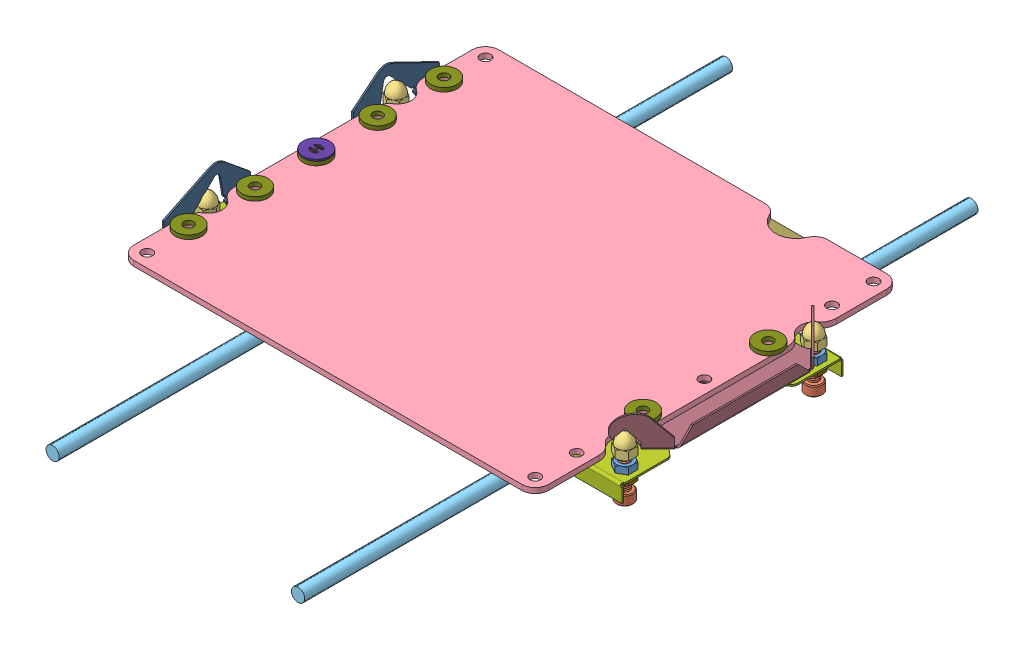
SolidWorks assembly Mendel_BedMount, configuration Default. Lengths in mm.
Overall size (275.81 70.12 406).
45 component instances, 20 part files, 73 mates.
Components (placement in the parent):
- M6_NutPress_99437A160-1: M6_NutPress_99437A160 [99437A160] at (-126 -5.9 57) x (0.191683 0 -0.981457) z (0 1 0) size (10 11.55 5.74)
- M6x24_95263A561-1: M6x24_95263A561 [95263A561] at (-126 4.0374 57) x (-0.390888 0 -0.920438) z (0 1 0) size (10 10 31.64)
- M6_NutAcorn_94000A038-1: M6_NutAcorn_94000A038 [94000A038] at (-126 -2.9626 57) x (-0.871894 0 0.489695) z (0 -1 0) size (10 11.55 12.42)
- GlassBed-1: GlassBed [Default] at origin size (250 3.17 220)
- Yaxis_Rod-1: Yaxis_Rod [Default] at (-74 -30 202) size (8 8 406)
- Yaxis_Rod-2: Yaxis_Rod [Default] at (74 -30 202) size (8 8 406)
- 8x25x37mm_LMUD8-1: 8x25x37mm_LMUD8 [Default] at (74 -30 -44) x (0 0 -1) z (-0.99999 -0.004469 0) size (37 15 15)
- 8x25x37mm_LMUD8-2: 8x25x37mm_LMUD8 [Default] at (74 -30 44) x (0 0 -1) z (0.967363 -0.253393 0) size (37 15 15)
- AluminumFrame^Mendel_BedMount-1: AluminumFrame^Mendel_BedMount [Default] at origin size (268 25 133.45)
- V-reinforcement^Mendel_BedMount-1: V-reinforcement^Mendel_BedMount [Default] at origin size (107 35.99 131.12)
- M6_NutAcorn_94000A038-2: M6_NutAcorn_94000A038 [94000A038] at (-126 -2.9626 -57) x (1 0 0) z (0 -1 0) size (10 11.55 12.42)
- M6_NutAcorn_94000A038-3: M6_NutAcorn_94000A038 [94000A038] at (126 -2.9626 -57) x (1 0 0) z (0 -1 0) size (10 11.55 12.42)
- M6_NutAcorn_94000A038-4: M6_NutAcorn_94000A038 [94000A038] at (126 -2.9626 57) x (1 0 0) z (0 -1 0) size (10 11.55 12.42)
- M6_NutPress_99437A160-2: M6_NutPress_99437A160 [99437A160] at (-126 -5.9 -57) x (1 0 0) z (0 1 0) size (10 11.55 5.74)
- M6_NutPress_99437A160-3: M6_NutPress_99437A160 [99437A160] at (126 -5.9 -57) x (1 0 0) z (0 1 0) size (10 11.55 5.74)
- M6_NutPress_99437A160-4: M6_NutPress_99437A160 [99437A160] at (126 -5.9 57) x (1 0 0) z (0 1 0) size (10 11.55 5.74)
- M6x24_95263A561-2: M6x24_95263A561 [95263A561] at (-126 4.0374 -57) x (0.977589 0 -0.210522) z (0 1 0) size (10 10 31.64)
- M6x24_95263A561-3: M6x24_95263A561 [95263A561] at (126 4.0374 -57) x (0.987041 0 0.160467) z (0 1 0) size (10 10 31.64)
- M6x24_95263A561-4: M6x24_95263A561 [95263A561] at (126 4.0374 57) x (-0.559971 0 -0.828512) z (0 1 0) size (10 10 31.64)
- Nut_M6_91828A251-1: Nut_M6_91828A251 [91828A251] at (-126 -13.516 -57) size (10 5.37 11.55)
- Nut_M6_91828A251-2: Nut_M6_91828A251 [91828A251] at (-126 -13.516 57) size (10 5.37 11.55)
- Nut_M6_91828A251-3: Nut_M6_91828A251 [91828A251] at (126 -13.516 57) size (10 5.37 11.55)
- Nut_M6_91828A251-4: Nut_M6_91828A251 [91828A251] at (126 -13.516 -57) size (10 5.37 11.55)
- Kinematic_A^Mendel_BedMount-1: Kinematic_A^Mendel_BedMount [Default] at origin size (31.19 23.27 52) (virtual)
- Kinematic_B^Mendel_BedMount-1: Kinematic_B^Mendel_BedMount [Default] at origin (suppressed, hidden, virtual)
- Kinematic_B^Mendel_BedMount-4: Kinematic_B^Mendel_BedMount [Default_Mirror] at origin (suppressed, hidden, virtual)
- Kinematic_A^Mendel_BedMount-4: Kinematic_A^Mendel_BedMount [_MirrorDefault] at origin size (31.19 23.27 52) (virtual)
- BearingClamp-1: BearingClamp [Default] at origin size (17.03 28.52 27.15) (hidden)
- BearingClamp-2: BearingClamp [Default] at (0 0 -88) size (17.03 28.52 27.15) (hidden)
- PCBheater-1: PCBheater [Default] at (0 -1.75 0) x (0 0 1) z (-1 0 0) size (214 1.75 214)
- Kinematic_C^Mendel_BedMount-1: Kinematic_C^Mendel_BedMount [Default] at origin size (42.61 21.87 125.3) (virtual)
- bearing_5x16x5-1: bearing_5x16x5 [Default] at (-74 -18 0) size (5 16 16)
- bearing_5x16x5-2: bearing_5x16x5 [Default] at (-74 -42 0) size (5 16 16)
- Bearing_Printed^Mendel_BedMount-1: Bearing_Printed^Mendel_BedMount [Default] at origin size (25 24.88 38) (virtual)
- 1-4_silicone_99604A115-1: 1-4_silicone_99604A115 [99604A115] at (-117 3.175 37) x (1 0 0) z (0 -1 0) size (15.88 15.88 2.36)
- 1-4_silicone_99604A115-2: 1-4_silicone_99604A115 [99604A115] at (-117 3.175 -37) x (1 0 0) z (0 -1 0) size (15.88 15.88 2.36)
- 1-4_silicone_99604A115-3: 1-4_silicone_99604A115 [99604A115] at (-117 3.175 77) x (1 0 0) z (0 -1 0) size (15.88 15.88 2.36)
- 1-4_silicone_99604A115-4: 1-4_silicone_99604A115 [99604A115] at (-117 3.175 -77) x (1 0 0) z (0 -1 0) size (15.88 15.88 2.36)
- 1-4_silicone_99604A115-5: 1-4_silicone_99604A115 [99604A115] at (-117.0025 3.175 0) x (1 0 0) z (0 -1 0) size (15.88 15.88 2.36)
- 1-4_silicone_99604A115-7: 1-4_silicone_99604A115 [99604A115] at (118.5 3.175 -37) x (0.283432 0 -0.958992) z (0 -1 0) size (15.88 15.88 2.36)
- 1-4_silicone_99604A115-8: 1-4_silicone_99604A115 [99604A115] at (117 3.175 37) x (1 0 0) z (0 -1 0) size (15.88 15.88 2.36)
- Spring_clamp^Mendel_BedMount-1: Spring_clamp^Mendel_BedMount [Default] at origin size (15.88 1.02 15.88) (virtual)
- AWS5_15-1: AWS5_15 [Default] at (-116.47 -8.0769 0.334) x (0.015915 0.999378 -0.031454) z (0.999709 -0.015333 0.018643) size (16.2 5 5)
- WSSS10-5-2.5-1: WSSS10-5-2.5 [Default] at (-69 -18 0) x (0 1 0) z (0 0 1) size (10 2.5 10)
- WSSS10-5-2.5-2: WSSS10-5-2.5 [Default] at (-69 -42 0) x (0 1 0) z (0 0 1) size (10 2.5 10)
Mates (geometry in assembly coordinates):
- Coincident5: coincident anti-aligned: cylinder of M6x24_95263A561-1 through (-126 -26.9626 57) axis (0 1 0) radius 5; circle of M6_NutAcorn_94000A038-1
- Concentric2: concentric anti-aligned: circle of M6_NutPress_99437A160-1; cylinder of M6x24_95263A561-1 through (-126 -26.9626 57) axis (0 1 0) radius 5
- Distance1: distance = 18 mm anti-aligned: plane of M6_NutAcorn_94000A038-1 through (-125.8814 -2.9626 47.0007) normal (0 -1 0); plane of M6x24_95263A561-1 through (-126 -20.9626 57) normal (0 1 0)
- Coincident9: coincident aligned: plane of GlassBed-1 through (0 0 0) normal (0 0 1); plane of assembly through (0 0 0) normal (0 0 1)
- Coincident10: coincident aligned: plane of GlassBed-1 through (0 0 0) normal (0 1 0); plane of assembly through (0 0 0) normal (0 1 0)
- Coincident11: coincident aligned: plane of GlassBed-1 through (0 0 0) normal (1 0 0); plane of assembly through (0 0 0) normal (1 0 0)
- Coincident16: coincident: plane of Yaxis_Rod-2 through (74 -30 -204) normal (0 0 -1); point of assembly
- Coincident17: coincident anti-aligned: cylinder of Yaxis_Rod-2 through (74 -30 202) axis (0 0 -1) radius 4; circle of assembly
- Coincident18: coincident: plane of Yaxis_Rod-1 through (-74 -30 -204) normal (0 0 -1); point of assembly
- Coincident19: coincident anti-aligned: cylinder of Yaxis_Rod-1 through (-74 -30 202) axis (0 0 -1) radius 4; circle of assembly
- Concentric4: concentric anti-aligned: cylinder of Yaxis_Rod-2 through (74 -30 202) axis (0 0 -1) radius 4; cylinder of 8x25x37mm_LMUD8-1 through (74 -30 -62.5) axis (0 0 1) radius 4
- Concentric5: concentric anti-aligned: cylinder of Yaxis_Rod-2 through (74 -30 202) axis (0 0 -1) radius 4; cylinder of 8x25x37mm_LMUD8-2 through (74 -30 25.5) axis (0 0 1) radius 4
- Concentric7: concentric aligned: cylinder of M6x24_95263A561-1 through (-126 -26.9626 57) axis (0 1 0) radius 5; cylinder of AluminumFrame^Mendel_BedMount-1 through (-126 -11.016 57) axis (0 1 0) radius 4
- Coincident22: coincident anti-aligned: plane of M6_NutPress_99437A160-1 through (-127.8748 -10 51.5394) normal (0 -1 0); plane of AluminumFrame^Mendel_BedMount-1 through (134 -10 66) normal (0 1 0)
- Concentric8: concentric anti-aligned: cylinder of AluminumFrame^Mendel_BedMount-1 through (-126 -11.016 -57) axis (0 1 0) radius 4; circle of M6_NutPress_99437A160-2
- Coincident23: coincident anti-aligned: plane of AluminumFrame^Mendel_BedMount-1 through (134 -10 66) normal (0 1 0); plane of M6_NutPress_99437A160-2 through (-121 -10 -59.8868) normal (0 -1 0)
- Concentric9: concentric anti-aligned: cylinder of AluminumFrame^Mendel_BedMount-1 through (126 -11.016 -57) axis (0 1 0) radius 4; circle of M6_NutPress_99437A160-3
- Coincident24: coincident anti-aligned: plane of AluminumFrame^Mendel_BedMount-1 through (134 -10 66) normal (0 1 0); plane of M6_NutPress_99437A160-3 through (131 -10 -59.8868) normal (0 -1 0)
- Concentric10: concentric anti-aligned: cylinder of AluminumFrame^Mendel_BedMount-1 through (126 -11.016 57) axis (0 1 0) radius 4; circle of M6_NutPress_99437A160-4
- Coincident25: coincident anti-aligned: plane of AluminumFrame^Mendel_BedMount-1 through (134 -10 66) normal (0 1 0); plane of M6_NutPress_99437A160-4 through (131 -10 54.1132) normal (0 -1 0)
- Concentric11: concentric anti-aligned: circle of M6_NutPress_99437A160-4; cylinder of M6x24_95263A561-4 through (126 -26.9626 57) axis (0 1 0) radius 5
- Concentric12: concentric anti-aligned: circle of M6_NutPress_99437A160-3; cylinder of M6x24_95263A561-3 through (126 -26.9626 -57) axis (0 1 0) radius 5
- Concentric13: concentric anti-aligned: circle of M6_NutPress_99437A160-2; cylinder of M6x24_95263A561-2 through (-126 -26.9626 -57) axis (0 1 0) radius 5
- Coincident26: coincident anti-aligned: circle of M6_NutAcorn_94000A038-2; cylinder of M6x24_95263A561-2 through (-126 -26.9626 -57) axis (0 1 0) radius 5
- Coincident27: coincident anti-aligned: circle of M6_NutAcorn_94000A038-3; cylinder of M6x24_95263A561-3 through (126 -26.9626 -57) axis (0 1 0) radius 5
- Coincident28: coincident anti-aligned: circle of M6_NutAcorn_94000A038-4; cylinder of M6x24_95263A561-4 through (126 -26.9626 57) axis (0 1 0) radius 5
- Distance6: distance = 18 mm anti-aligned: plane of M6x24_95263A561-4 through (126 -20.9626 57) normal (0 1 0); plane of M6_NutAcorn_94000A038-4 through (121 -2.9626 65.6603) normal (0 -1 0)
- Distance7: distance = 18 mm anti-aligned: plane of M6x24_95263A561-3 through (126 -20.9626 -57) normal (0 1 0); plane of M6_NutAcorn_94000A038-3 through (121 -2.9626 -48.3397) normal (0 -1 0)
- Distance8: distance = 18 mm anti-aligned: plane of M6_NutAcorn_94000A038-2 through (-131 -2.9626 -48.3397) normal (0 -1 0); plane of M6x24_95263A561-2 through (-126 -20.9626 -57) normal (0 1 0)
- Coincident32: coincident aligned: plane of M6x24_95263A561-3 through (126 -26.9626 -57) normal (0 -1 0); plane of M6x24_95263A561-4 through (126 -26.9626 57) normal (0 -1 0)
- Coincident33: coincident aligned: plane of M6x24_95263A561-1 through (-126 -26.9626 57) normal (0 -1 0); plane of M6x24_95263A561-4 through (126 -26.9626 57) normal (0 -1 0)
- Coincident34: coincident aligned: plane of M6x24_95263A561-1 through (-126 -26.9626 57) normal (0 -1 0); plane of M6x24_95263A561-2 through (-126 -26.9626 -57) normal (0 -1 0)
- Coincident35: coincident anti-aligned: cylinder of M6x24_95263A561-2 through (-126 -26.9626 -57) axis (0 1 0) radius 5; circle of Nut_M6_91828A251-1
- Coincident36: coincident anti-aligned: cylinder of M6x24_95263A561-1 through (-126 -26.9626 57) axis (0 1 0) radius 5; circle of Nut_M6_91828A251-2
- Coincident37: coincident anti-aligned: cylinder of M6x24_95263A561-4 through (126 -26.9626 57) axis (0 1 0) radius 5; circle of Nut_M6_91828A251-3
- Coincident38: coincident anti-aligned: cylinder of M6x24_95263A561-3 through (126 -26.9626 -57) axis (0 1 0) radius 5; circle of Nut_M6_91828A251-4
- Coincident39: coincident anti-aligned: plane of AluminumFrame^Mendel_BedMount-1 through (134 -11.016 66) normal (0 -1 0); plane of Nut_M6_91828A251-4 through (131 -11.016 -59.8868) normal (0 1 0)
- Coincident40: coincident anti-aligned: plane of AluminumFrame^Mendel_BedMount-1 through (134 -11.016 66) normal (0 -1 0); plane of Nut_M6_91828A251-3 through (131 -11.016 54.1132) normal (0 1 0)
- Coincident41: coincident anti-aligned: plane of AluminumFrame^Mendel_BedMount-1 through (134 -11.016 66) normal (0 -1 0); plane of Nut_M6_91828A251-2 through (-121 -11.016 54.1132) normal (0 1 0)
- Coincident42: coincident anti-aligned: plane of AluminumFrame^Mendel_BedMount-1 through (134 -11.016 66) normal (0 -1 0); plane of Nut_M6_91828A251-1 through (-121 -11.016 -59.8868) normal (0 1 0)
- Distance9: distance = 125 mm anti-aligned: plane of 8x25x37mm_LMUD8-1 through (74.0179 -34 -62.5) normal (0 0 -1); plane of 8x25x37mm_LMUD8-2 through (75.7991 -23.1317 62.5) normal (0 0 1)
- Symmetric1: symmetric aligned: plane of GlassBed-1 through (0 0 0) normal (0 0 1); plane of 8x25x37mm_LMUD8-1 through (74.0317 -37.0999 -25.5) normal (0 0 1); plane of 8x25x37mm_LMUD8-2 through (75.0136 -26.1305 25.5) normal (0 0 -1)
- Concentric14: concentric aligned: cylinder of 8x25x37mm_LMUD8-1 through (74 -30 -62.5) axis (0 0 1) radius 7.5; cylinder of BearingClamp-2 through (74 -30 -32.15) axis (0 0 1) radius 7.5
- Symmetric2: symmetric aligned: plane of GlassBed-1 through (0 0 0) normal (0 0 1); plane of BearingClamp-2 through (74.0917 -30 -30.4257) normal (0 0 1); plane of BearingClamp-1 through (115.1917 -30 30.4257) normal (0 0 -1)
- Coincident43: coincident anti-aligned: plane of GlassBed-1 through (-125 0 110) normal (0 -1 0); plane of PCBheater-1 through (-107 0 -107) normal (0 1 0)
- Coincident44: coincident anti-aligned: plane of PCBheater-1 through (0 -1.75 0) normal (-1 0 0); plane of assembly through (0 0 0) normal (1 0 0)
- Coincident45: coincident aligned: plane of PCBheater-1 through (0 -1.75 0) normal (0 0 1); plane of assembly through (0 0 0) normal (0 0 1)
- Concentric16: concentric anti-aligned: cylinder of bearing_5x16x5-1 through (-76.5 -18 0) axis (-1 0 0) radius 8; line of assembly
- Concentric17: concentric anti-aligned: cylinder of bearing_5x16x5-2 through (-76.5 -42 0) axis (-1 0 0) radius 8; line of assembly
- Coincident48: coincident: plane of bearing_5x16x5-2 through (-71.5 -38.5 0) normal (1 0 0); line of assembly
- Coincident49: coincident: plane of bearing_5x16x5-1 through (-71.5 -14.5 0) normal (1 0 0); line of assembly
- Concentric18: concentric anti-aligned: cylinder of Kinematic_A^Mendel_BedMount-4 through (-117 -1.016 37) axis (0 1 0) radius 3.2; cylinder of 1-4_silicone_99604A115-1 through (-117 5.5372 37) axis (0 -1 0) radius 7.9375
- Concentric19: concentric anti-aligned: cylinder of Kinematic_A^Mendel_BedMount-1 through (-117 -1.016 -37) axis (0 1 0) radius 3.2; cylinder of 1-4_silicone_99604A115-2 through (-117 5.5372 -37) axis (0 -1 0) radius 7.9375
- Concentric20: concentric anti-aligned: cylinder of Kinematic_A^Mendel_BedMount-4 through (-117 -1.016 77) axis (0 1 0) radius 3.2; cylinder of 1-4_silicone_99604A115-3 through (-117 5.5372 77) axis (0 -1 0) radius 7.9375
- Concentric21: concentric anti-aligned: cylinder of Kinematic_A^Mendel_BedMount-1 through (-117 -1.016 -77) axis (0 1 0) radius 3.2; cylinder of 1-4_silicone_99604A115-4 through (-117 5.5372 -77) axis (0 -1 0) radius 7.9375
- Concentric22: concentric anti-aligned: cylinder of GlassBed-1 through (-117.0025 0 0) axis (0 1 0) radius 3.2; cylinder of 1-4_silicone_99604A115-5 through (-117.0025 5.5372 0) axis (0 -1 0) radius 7.9375
- Concentric24: concentric anti-aligned: cylinder of Kinematic_C^Mendel_BedMount-1 through (118.5 -1.016 -37) axis (0 1 0) radius 3.2; cylinder of 1-4_silicone_99604A115-7 through (118.5 5.5372 -37) axis (0 -1 0) radius 7.9375
- Concentric25: concentric anti-aligned: cylinder of GlassBed-1 through (117 0 37) axis (0 1 0) radius 3.2; cylinder of 1-4_silicone_99604A115-8 through (117 5.5372 37) axis (0 -1 0) radius 7.9375
- Coincident50: coincident anti-aligned: plane of GlassBed-1 through (-125 3.175 110) normal (0 1 0); plane of 1-4_silicone_99604A115-8 through (117 3.175 37) normal (0 -1 0)
- Coincident51: coincident anti-aligned: plane of GlassBed-1 through (-125 3.175 110) normal (0 1 0); plane of 1-4_silicone_99604A115-7 through (118.5 3.175 -37) normal (0 -1 0)
- Coincident52: coincident anti-aligned: plane of GlassBed-1 through (-125 3.175 110) normal (0 1 0); plane of 1-4_silicone_99604A115-3 through (-117 3.175 77) normal (0 -1 0)
- Coincident53: coincident anti-aligned: plane of GlassBed-1 through (-125 3.175 110) normal (0 1 0); plane of 1-4_silicone_99604A115-5 through (-117.0025 3.175 0) normal (0 -1 0)
- Coincident54: coincident anti-aligned: plane of GlassBed-1 through (-125 3.175 110) normal (0 1 0); plane of 1-4_silicone_99604A115-1 through (-117 3.175 37) normal (0 -1 0)
- Coincident55: coincident anti-aligned: plane of GlassBed-1 through (-125 3.175 110) normal (0 1 0); plane of 1-4_silicone_99604A115-2 through (-117 3.175 -37) normal (0 -1 0)
- Coincident56: coincident anti-aligned: plane of GlassBed-1 through (-125 3.175 110) normal (0 1 0); plane of 1-4_silicone_99604A115-4 through (-117 3.175 -77) normal (0 -1 0)
- Coincident57: coincident anti-aligned: plane of V-reinforcement^Mendel_BedMount-1 through (-69 -11.74 -12) normal (-1 0 0); plane of WSSS10-5-2.5-1 through (-69 -18 0) normal (1 0 0)
- Coincident58: coincident anti-aligned: plane of V-reinforcement^Mendel_BedMount-1 through (-69 -11.74 -12) normal (-1 0 0); plane of WSSS10-5-2.5-2 through (-69 -42 0) normal (1 0 0)
- Concentric26: concentric anti-aligned: cylinder of bearing_5x16x5-1 through (-76.5 -18 0) axis (-1 0 0) radius 2.5; cylinder of WSSS10-5-2.5-1 through (-71.5 -18 0) axis (1 0 0) radius 5
- Concentric27: concentric anti-aligned: cylinder of bearing_5x16x5-2 through (-76.5 -42 0) axis (-1 0 0) radius 2.5; cylinder of WSSS10-5-2.5-2 through (-71.5 -42 0) axis (1 0 0) radius 2.5
- Sketch3: unknown: unknown of ?; unknown of ?; unknown of ?; unknown of ?; unknown of ?; unknown of ?; unknown of ?; unknown of ?; unknown of ?; unknown of ?; unknown of ?; unknown of ?; unknown of ?; unknown of ?; unknown of ?; unknown of ?; unknown of ?; unknown of ?; unknown of Yaxis_Rod-1; unknown of 8x25x37mm_LMUD8-1; unknown of Yaxis_Rod-1; unknown of 8x25x37mm_LMUD8-1; unknown of Yaxis_Rod-1; unknown of Yaxis_Rod-1
- Sketch4: unknown: axis of ? through (-117 0 -77) axis (0 1 0); line of ? through (-117 0 -37) axis (0 1 0); unknown of ?; unknown of ?; unknown of ?; unknown of PCBheater-1; unknown of ?; unknown of ?; unknown of ?; unknown of ?; unknown of ?; unknown of ?; unknown of ?
- MirrorComponent6: unknown: plane of ? through (0 0 0) normal (0 0 1)
- PLANE2: unknown: cylinder of 8x25x37mm_LMUD8-2 through (74 -30 25.5) axis (0 0 1) radius 7.5; unknown of Yaxis_Rod-2; unknown of Yaxis_Rod-2; unknown of 8x25x37mm_LMUD8-2; unknown of 8x25x37mm_LMUD8-2; unknown of ?; unknown of ?; unknown of 8x25x37mm_LMUD8-2; unknown of 8x25x37mm_LMUD8-2; unknown of ?; unknown of ?; unknown of ?; unknown of ?; unknown of ?; unknown of ?; unknown of ?; unknown of ?; unknown of ?; unknown of ?; unknown of ?; unknown of ?; unknown of ?; unknown of ?; unknown of ?; unknown of ?; unknown of ?; unknown of PCBheater-1; unknown of PCBheater-1; unknown of ?; unknown of ?; unknown of ?; unknown of M6_NutAcorn_94000A038-4; unknown of M6_NutAcorn_94000A038-4; unknown of ?; unknown of M6_NutAcorn_94000A038-4; unknown of M6_NutAcorn_94000A038-4; unknown of M6_NutAcorn_94000A038-3; unknown of ?; unknown of ?; unknown of ?; unknown of ?; unknown of ?; unknown of ?; unknown of ?; unknown of ?; unknown of ?; unknown of ?; unknown of ?; unknown of ?; unknown of ?; unknown of ?; unknown of ?; unknown of ?; unknown of ?; unknown of ?; unknown of ?; unknown of ?; unknown of ?; unknown of ?; unknown of ?; unknown of ?; unknown of ?; unknown of ?; unknown of ?; unknown of ?; unknown of ?; unknown of ?; unknown of ?; unknown of ?; unknown of ?; unknown of ?; unknown of ?; unknown of ?; unknown of ?; unknown of ?; unknown of ?; unknown of ?; unknown of ?; unknown of ?; unknown of ?; unknown of ?; unknown of ?; unknown of ?; unknown of ?; unknown of ?; unknown of BearingClamp-2; unknown of BearingClamp-2; unknown of 8x25x37mm_LMUD8-2; unknown of 8x25x37mm_LMUD8-1; unknown of 8x25x37mm_LMUD8-2; unknown of 8x25x37mm_LMUD8-1; unknown of ?; unknown of ?; unknown of 8x25x37mm_LMUD8-1; unknown of 8x25x37mm_LMUD8-1; unknown of 8x25x37mm_LMUD8-1; unknown of 8x25x37mm_LMUD8-1; unknown of 8x25x37mm_LMUD8-1; unknown of ?; unknown of ?; unknown of ?; unknown of ?; unknown of ?; unknown of ?; unknown of 1-4_silicone_99604A115-5; unknown of ?; unknown of ?; unknown of 1-4_silicone_99604A115-5; unknown of ?; unknown of ?; unknown of ?; unknown of ?; unknown of ?; unknown of ?; unknown of 1-4_silicone_99604A115-5
